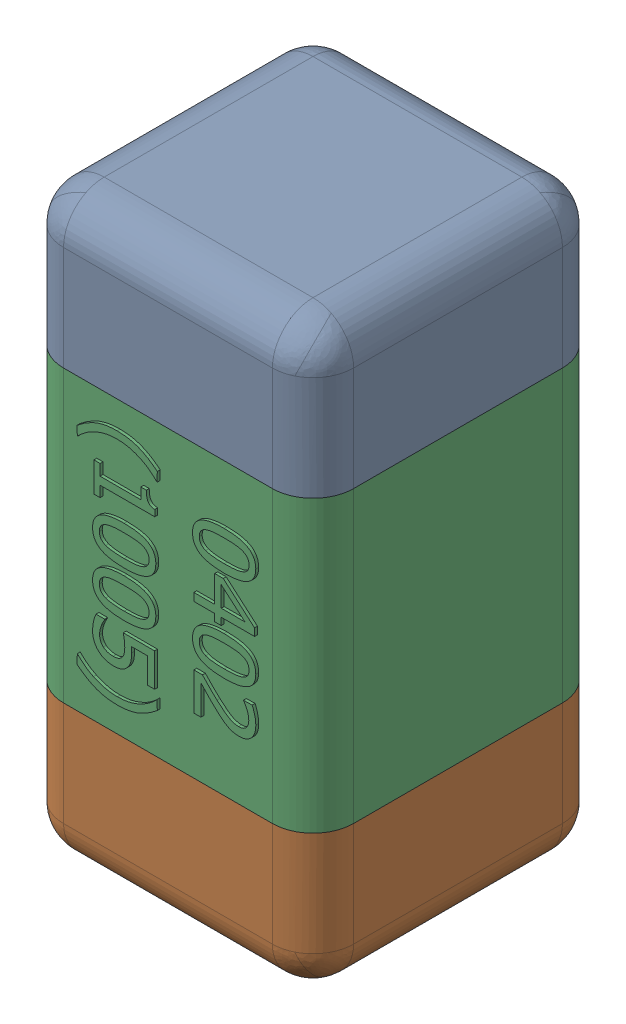
SolidWorks assembly C40, configuration Standard. Lengths in mm.
Overall size (0.51 1.01 0.51).
4 component instances, 3 part files, 0 mates.
Components (placement in the parent):
- C40-subassembly-1-1: C40-subassembly-1 [Standard] at (-14.4 17.0999 0) x (0 -1 0) z (0 0 1) size (1.01 0.51 0.51)
  - User Library-0402_Cap-1: User Library-0402_Cap [Standard] at origin size (0.26 0.51 0.51)
  - User Library-0402_Cap-1-1: User Library-0402_Cap-1 [Standard] at origin size (0.26 0.5 0.51)
  - User Library-0402_Cap-2-1: User Library-0402_Cap-2 [Standard] at origin size (0.5 0.5 0.51)
